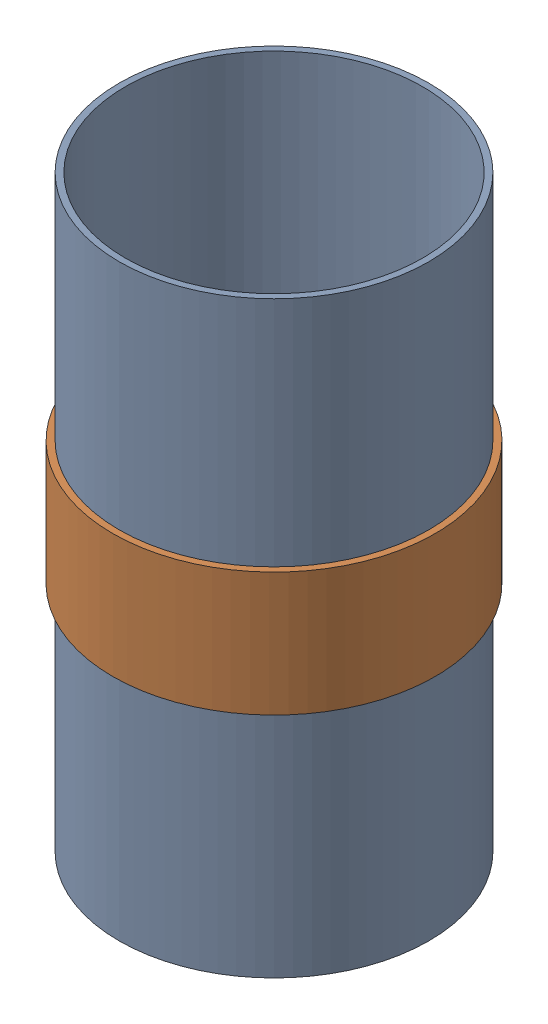
SolidWorks assembly subscale_recoverybay, configuration Default. Lengths in mm.
Overall size (79.35 144.78 79.35).
2 component instances, 2 part files, 5 mates.
Components (placement in the parent):
- subscale_coupler-2: subscale_coupler [Default] at origin size (76.2 144.78 76.2)
- subscale_switchband-2: subscale_switchband [Default] at origin size (79.35 30.48 79.35)
Mates (geometry in assembly coordinates):
- Coincident5: coincident aligned: plane of subscale_recoverybay-2 through (0 0 0) normal (0 1 0)
- Coincident6: coincident aligned: plane of subscale_recoverybay-2 through (0 0 0) normal (0 0 1)
- Coincident7: coincident aligned: plane of subscale_recoverybay-2 through (0 0 0) normal (1 0 0)
- Coincident8: coincident aligned: plane of subscale_recoverycoupler-2 through (44.8237 0 -74.1315) normal (0 1 0)
- Concentric1: concentric aligned: cylinder of subscale_recoverybay-2 through (0 72.39 0) axis (0 -1 0) radius 36.576; cylinder of subscale_recoverycoupler-2 through (0 15.24 0) axis (0 -1 0) radius 38.1
